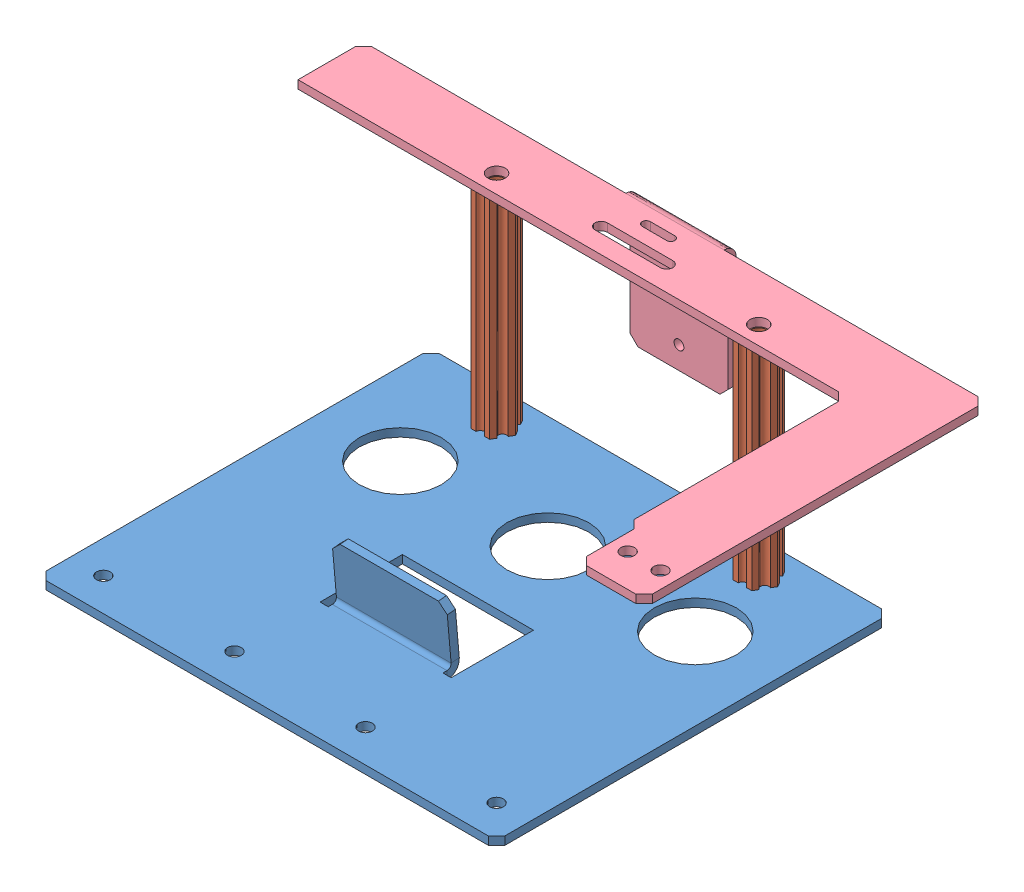
SolidWorks assembly BatBox!Top, configuration Default. Lengths in mm.
Overall size (241.3 93.09 162.75).
6 component instances, 4 part files, 10 mates.
Components (placement in the parent):
- am-3959 AM14U4 Vertical Battery Mount Floor Plate-1: am-3959 AM14U4 Vertical Battery Mount Floor Plate [Default] at (-22.9363 77.673 216.7192) size (177.8 25.3 152.4)
- am-churro 3_385 churro tube-1: am-churro 3_385 churro tube [Default] at (15.1637 158.826 77.0192) x (1 0 0) z (0 -1 0) size (14.66 12.7 81.15)
- am-churro 3_385 churro tube-2: am-churro 3_385 churro tube [Default] at (116.7637 158.826 77.0192) x (1 0 0) z (0 -1 0) size (14.66 12.7 81.15)
- FHTS 0.25-20-0.75-3: FHTS 0.25-20-0.75 [FHTS 0.25-20-G-0.75-C] at (116.7637 74.498 77.0192) x (0 1 0) z (0 0 1) size (24.64 12.19 12.19)
- FHTS 0.25-20-0.75-4: FHTS 0.25-20-0.75 [FHTS 0.25-20-G-0.75-C] at (15.1637 74.498 77.0192) x (0 1 0) z (0 0 1) size (24.64 12.19 12.19)
- am-3958 AM14U4 Vertical Battery Mount L-1: am-3958 AM14U4 Vertical Battery Mount L [Default] at (-54.6863 158.826 191.3192) size (241.3 50.8 137.35)
Mates (geometry in assembly coordinates):
- Concentric3: concentric aligned: cylinder of am-3959 AM14U4 Vertical Battery Mount Floor Plate-1 through (116.7637 74.498 77.0192) axis (0 1 0) radius 3.3782; cylinder of am-churro 3_385 churro tube-2 through (116.7637 -145.974 77.0192) axis (0 1 0) radius 2.9337
- Coincident2: coincident anti-aligned: plane of am-3959 AM14U4 Vertical Battery Mount Floor Plate-1 through (-22.9363 77.673 216.7192) normal (0 1 0); plane of am-churro 3_385 churro tube-2 through (116.7637 77.673 77.0192) normal (0 -1 0)
- Coincident4: coincident anti-aligned: plane of am-3959 AM14U4 Vertical Battery Mount Floor Plate-1 through (-22.9363 77.673 216.7192) normal (0 1 0); plane of am-churro 3_385 churro tube-1 through (15.1637 77.673 77.0192) normal (0 -1 0)
- Concentric71: concentric anti-aligned: cylinder of am-3959 AM14U4 Vertical Battery Mount Floor Plate-1 through (116.7637 74.498 77.0192) axis (0 1 0) radius 3.3782; cylinder of FHTS 0.25-20-0.75-3 through (116.7637 74.498 77.0192) axis (0 -1 0) radius 3.175
- Coincident71: coincident anti-aligned: plane of am-3959 AM14U4 Vertical Battery Mount Floor Plate-1 through (-22.9363 74.498 216.7192) normal (0 -1 0); plane of FHTS 0.25-20-0.75-3 through (113.5887 74.498 77.0192) normal (0 1 0)
- Concentric81: concentric anti-aligned: cylinder of am-3959 AM14U4 Vertical Battery Mount Floor Plate-1 through (15.1637 74.498 77.0192) axis (0 1 0) radius 3.3782; cylinder of FHTS 0.25-20-0.75-4 through (15.1637 74.498 77.0192) axis (0 -1 0) radius 3.175
- Coincident81: coincident anti-aligned: plane of am-3959 AM14U4 Vertical Battery Mount Floor Plate-1 through (-22.9363 74.498 216.7192) normal (0 -1 0); plane of FHTS 0.25-20-0.75-4 through (11.9887 74.498 77.0192) normal (0 1 0)
- Concentric82: concentric anti-aligned: cylinder of am-churro 3_385 churro tube-1 through (15.1637 -145.974 77.0192) axis (0 1 0) radius 2.9337; cylinder of am-3958 AM14U4 Vertical Battery Mount L-1 through (15.1637 162.001 77.0192) axis (0 -1 0) radius 3.3782
- Concentric83: concentric anti-aligned: cylinder of am-churro 3_385 churro tube-2 through (116.7637 -145.974 77.0192) axis (0 1 0) radius 2.9337; cylinder of am-3958 AM14U4 Vertical Battery Mount L-1 through (116.7637 162.001 77.0192) axis (0 -1 0) radius 3.3782
- Coincident83: coincident anti-aligned: plane of am-churro 3_385 churro tube-2 through (122.2629 158.826 80.1942) normal (0 1 0); plane of am-3958 AM14U4 Vertical Battery Mount L-1 through (-54.6863 158.826 191.3192) normal (0 -1 0)
